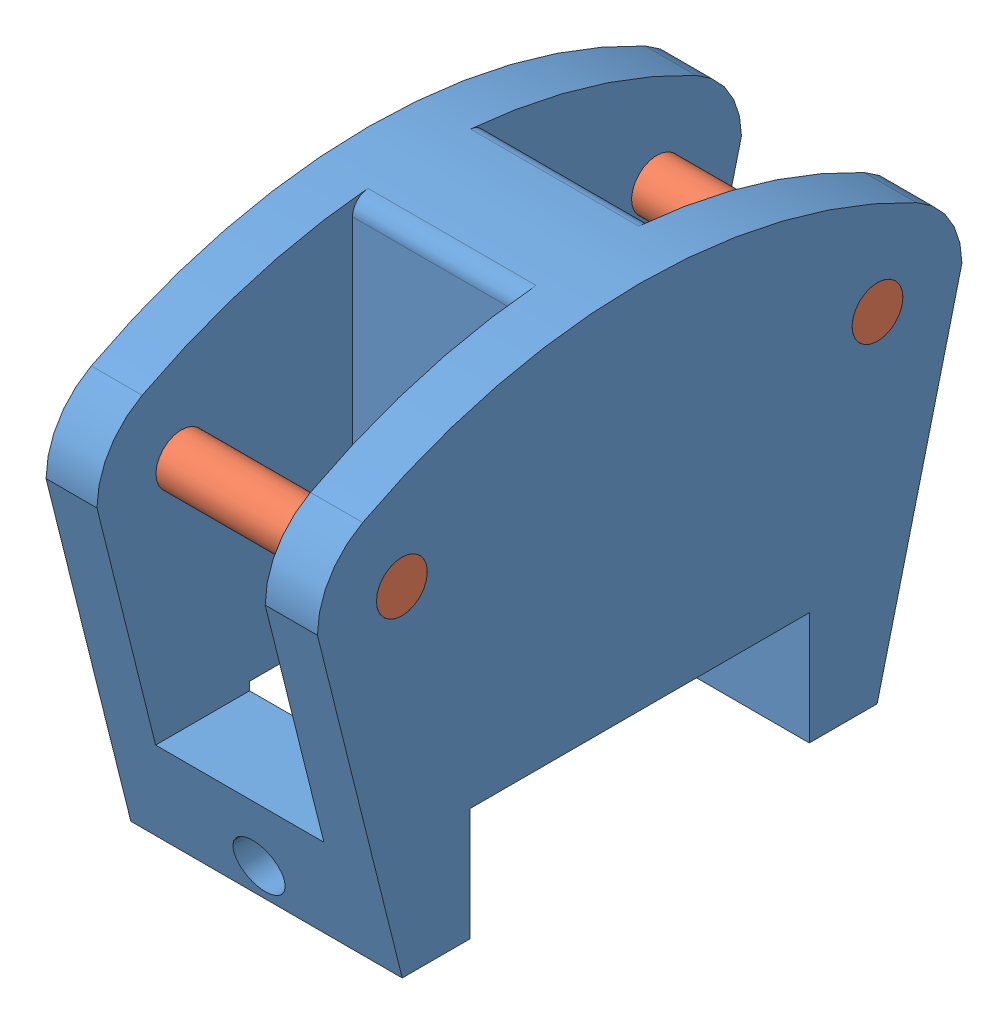
SolidWorks assembly JointShaft, configuration Default. Lengths in mm.
Overall size (18 28.47 38).
3 component instances, 2 part files, 4 mates.
Components (placement in the parent):
- Joint-1: Joint [Default] at (3.0563 9.2049 28.3678) size (16 28.47 38)
- shaft-1: shaft [Default] at (19.0563 29.2049 42.3888) x (0 0.84865 0.528954) z (-1 0 0) size (3 3 18)
- shaft-2: shaft [Default] at (19.0563 29.2049 14.3467) x (0 0.997691 0.067922) z (-1 0 0) size (3 3 18)
Mates (geometry in assembly coordinates):
- Concentric1: concentric anti-aligned: cylinder of Joint-1 through (19.0563 29.2049 42.3888) axis (-1 0 0) radius 1.5; cylinder of shaft-1 through (1.0563 29.2049 42.3888) axis (1 0 0) radius 1.5
- Concentric2: concentric anti-aligned: cylinder of Joint-1 through (19.0563 29.2049 14.3467) axis (-1 0 0) radius 1.5; cylinder of shaft-2 through (1.0563 29.2049 14.3467) axis (1 0 0) radius 1.5
- Coincident1: coincident aligned: circle of Joint-1; plane of shaft-1 through (19.0563 29.2049 42.3888) normal (1 0 0)
- Coincident2: coincident anti-aligned: circle of Joint-1; plane of shaft-2 through (19.0563 29.2049 14.3467) normal (1 0 0)
